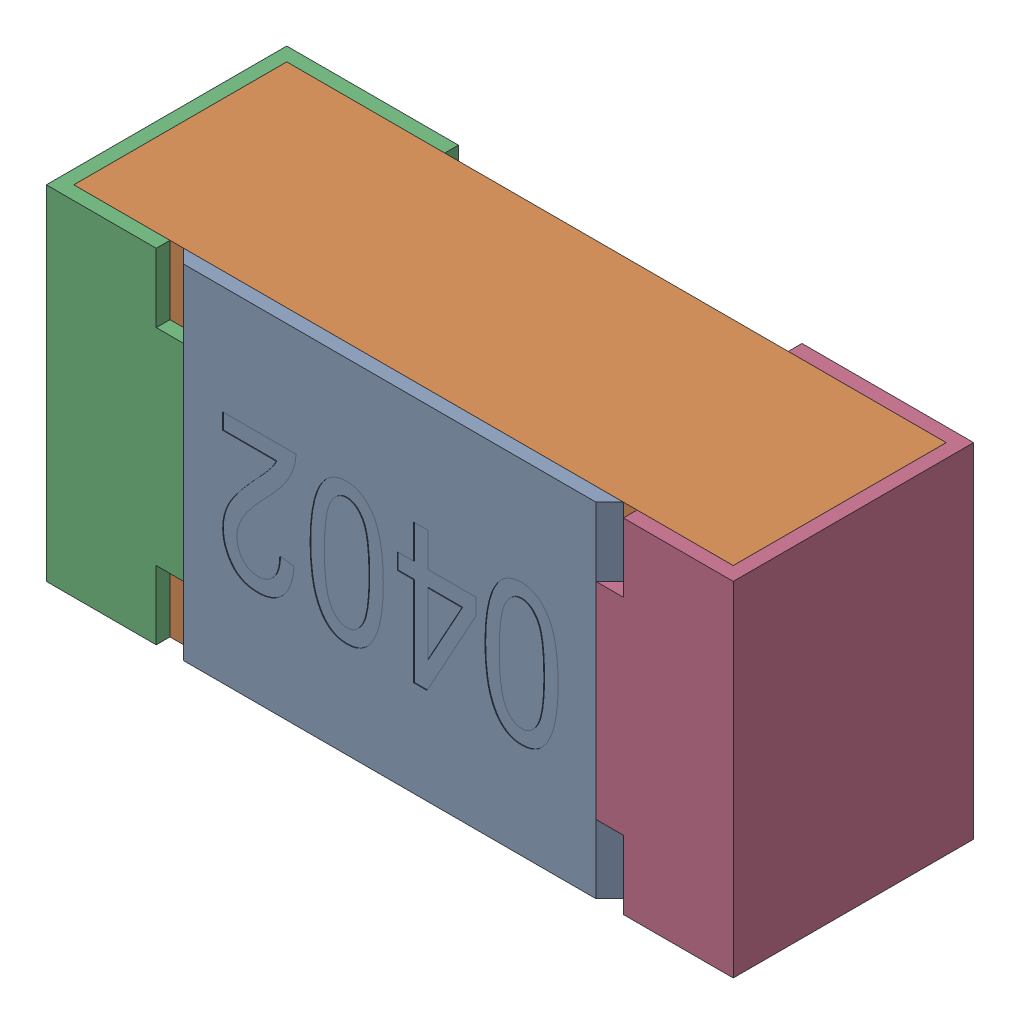
SolidWorks assembly R3, configuration Standard. Lengths in mm.
Overall size (1 0.5 0.35).
5 component instances, 4 part files, 0 mates.
Components (placement in the parent):
- R3-subassembly-1-1: R3-subassembly-1 [Standard] at (1.2999 -4.1 0) x (-1 0 0) z (0 0 1) size (1 0.5 0.35)
  - User Library-R_0402-1: User Library-R_0402 [Standard] at origin size (0.64 0.5 0.02)
  - User Library-R_0402-1-1: User Library-R_0402-1 [Standard] at origin size (0.96 0.5 0.31)
  - User Library-R_0402-2-1: User Library-R_0402-2 [Standard] at origin size (0.25 0.5 0.35)
  - User Library-R_0402-3-1: User Library-R_0402-3 [Standard] at origin size (0.25 0.5 0.35)
